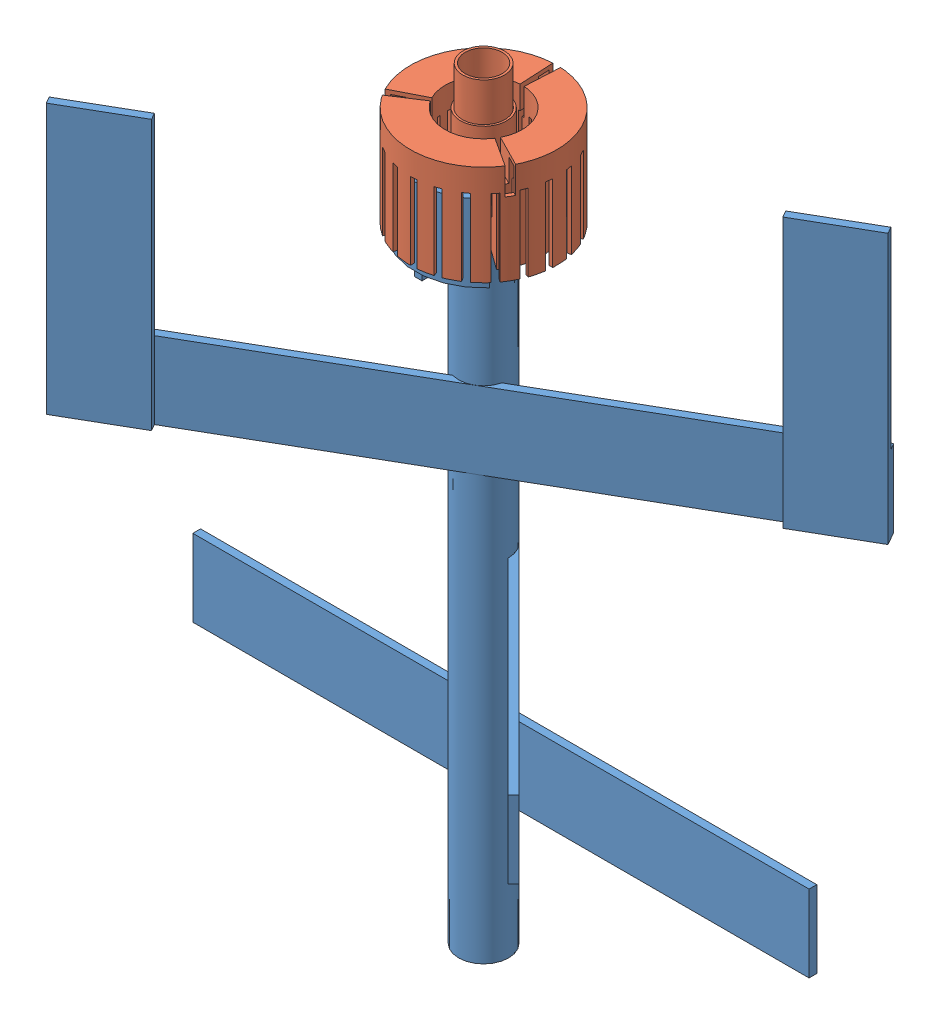
SolidWorks assembly Melangeur et fourreau, configuration Default. Lengths in mm.
Overall size (800 990 572.76).
2 component instances, 2 part files, 2 mates.
Components (placement in the parent):
- Bras multipales soudees evo1-1: Bras multipales soudees evo1 [Défaut] at (555.5101 97.6578 474.7509) size (800 900 572.76)
- FOURREAU fixe fond-1: FOURREAU fixe fond [Défaut] at (555.5101 907.6578 474.7509) size (190 180 190)
Mates (geometry in assembly coordinates):
- Coaxiale1: concentric aligned: cylinder of Bras multipales soudees evo1-1 through (555.5101 897.6578 474.7509) axis (0 -1 0) radius 32.5; cylinder of FOURREAU fixe fond-1 through (555.5101 1087.6578 474.7509) axis (0 -1 0) radius 24.0528
- Distance1: distance = 10 mm anti-aligned: plane of Bras multipales soudees evo1-1 through (555.5101 897.6578 474.7509) normal (0 1 0); plane of FOURREAU fixe fond-1 through (555.5101 907.6578 474.7509) normal (0 -1 0)
